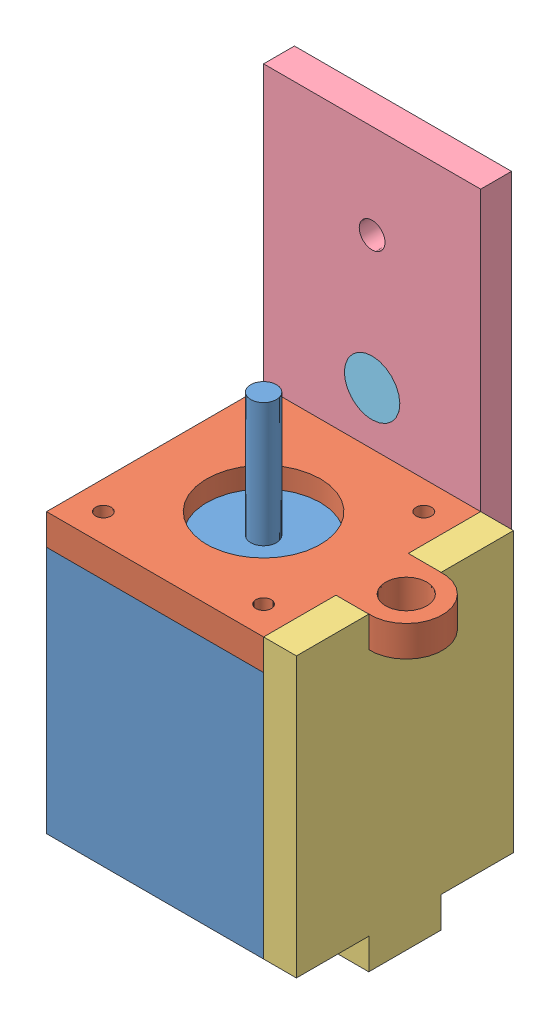
SolidWorks assembly yMotorAssem, configuration Default. Lengths in mm.
Overall size (55.6 113.97 53.94).
6 component instances, 5 part files, 14 mates.
Components (placement in the parent):
- motor-1: motor [Default] at (-14.7728 3.9195 87.5271) size (42 74 42)
- yMotorMountFace-1: yMotorMountFace [Default] at (-14.7728 51.9195 87.5271) size (55.6 5.97 47.97)
- yMotorMountToBotttom-1: yMotorMountToBotttom [Default] at (33.5772 3.9195 45.5271) x (0 0 1) z (0 -1 0) size (42 6.35 59.94)
- yMotorMountAngleSide-2: yMotorMountAngleSide [Default] at (-14.7728 51.9195 39.5581) x (1 0 0) z (0 -1 0) size (42 5.97 108)
- dot-1: dot [Default] at (6.2272 68.1195 45.5271) x (-0.950724 -0.310039 0) z (0.310039 -0.950724 0) size (10.7 5.97 10.7)
- dot-2: dot [Default] at (6.2272 68.1195 33.5891) x (-0.462045 0.886857 0) z (0.886857 0.462045 0) size (10.7 5.97 10.7)
Mates (geometry in assembly coordinates):
- Coincident5: coincident anti-aligned: circle of motor-1; cylinder of yMotorMountFace-1 through (6.2272 57.8885 66.5271) axis (0 -1 0) radius 11
- Coincident6: coincident anti-aligned: plane of motor-1 through (-14.7728 51.9195 87.5271) normal (0 1 0); plane of yMotorMountFace-1 through (-14.7728 51.9195 87.5271) normal (0 -1 0)
- Coincident7: coincident aligned: plane of motor-1 through (-14.7728 51.9195 87.5271) normal (0 0 1); plane of yMotorMountFace-1 through (-14.7728 57.8885 87.5271) normal (0 0 1)
- Coincident8: coincident anti-aligned: plane of yMotorMountFace-1 through (-14.7728 51.9195 87.5271) normal (0 -1 0); plane of yMotorMountToBotttom-1 through (27.2272 51.9195 59.5271) normal (0 1 0)
- Coincident9: coincident anti-aligned: plane of yMotorMountFace-1 through (27.2272 57.8885 87.5271) normal (1 0 0); plane of yMotorMountToBotttom-1 through (27.2272 3.9195 45.5271) normal (-1 0 0)
- Coincident10: coincident anti-aligned: plane of yMotorMountFace-1 through (27.2272 51.9195 73.5271) normal (0 0 1); plane of yMotorMountToBotttom-1 through (27.2272 51.9195 73.5271) normal (0 0 -1)
- Coincident12: coincident anti-aligned: plane of yMotorMountFace-1 through (-14.7728 57.8885 87.5271) normal (0 1 0); plane of yMotorMountAngleSide-2 through (-0.7728 57.8885 45.5271) normal (0 -1 0)
- Coincident13: coincident aligned: plane of yMotorMountFace-1 through (-0.7728 51.9195 39.5581) normal (0 0 -1); plane of yMotorMountAngleSide-2 through (-14.7728 51.9195 39.5581) normal (0 0 -1)
- Coincident14: coincident anti-aligned: plane of yMotorMountFace-1 through (13.2272 51.9195 39.5581) normal (1 0 0); plane of yMotorMountAngleSide-2 through (13.2272 57.8885 45.5271) normal (-1 0 0)
- Concentric2: concentric anti-aligned: cylinder of yMotorMountAngleSide-2 through (6.2272 68.1195 45.5271) axis (0 0 -1) radius 5.35; cylinder of dot-1 through (6.2272 68.1195 39.5581) axis (0 0 1) radius 5.35
- Coincident15: coincident aligned: plane of yMotorMountAngleSide-2 through (-14.7728 51.9195 39.5581) normal (0 0 -1); plane of dot-1 through (6.2272 68.1195 39.5581) normal (0 0 -1)
- Coincident16: coincident anti-aligned: plane of dot-1 through (6.2272 68.1195 39.5581) normal (0 0 -1); plane of dot-2 through (6.2272 68.1195 39.5581) normal (0 0 1)
- Coincident17: coincident aligned: circle of yMotorMountAngleSide-2; circle of dot-2
- Parallel1: parallel: line of yMotorMountAngleSide-2 through (27.2272 3.9195 39.5581) axis (0 1 0); plane of dot-2 through (6.2272 68.1195 33.5891) normal (0 0 -1)
